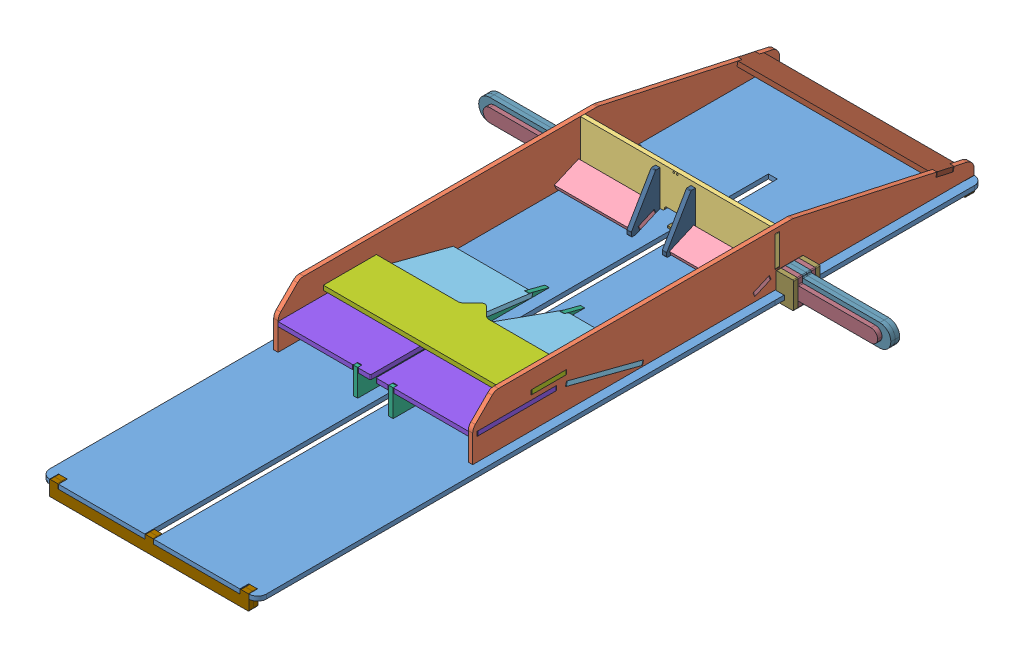
SolidWorks assembly assembly plane folder, configuration Default. Lengths in mm.
Overall size (466 77 820).
30 component instances, 16 part files, 6 mates.
Components (placement in the parent):
- frame-1: frame [Default] at (-2.7129 -3.6474 600) size (245.6 77 820)
  - backplate-1: backplate [Default] at (-118.702 1.298 900) size (245.6 5 820)
  - side-1: side [Default] at (-108.702 86.298 910) x (0 -1 0) z (1 0 0) size (65 566.78 5)
  - side-2: side [Default] at (111.298 86.298 910) x (0 -1 0) z (1 0 0) size (65 566.78 5)
  - frame-folder-1: frame-folder [Default] at (-103.702 21.248 530) size (225 45 5)
  - frame-folder2-1: frame-folder2 [Default] at (111.298 13.9006 564.4496) x (-1 0 0) z (0 -0.916515 -0.4) size (95 30 5)
  - frame-folder2-2: frame-folder2 [Default] at (-18.702 13.8606 564.5413) x (-1 0 0) z (0 -0.916515 -0.4) size (95 30 5)
  - frame-secondfold-1: frame-secondfold [Default] at (-103.702 31.4463 776.7345) x (1 0 0) z (0 0.967829 -0.251609) size (109.34 100 5)
  - frame-secondfold3-1: frame-secondfold3 [Default] at (-18.702 1.298 906.1881) x (0 0 -1) z (1 0 0) size (216.66 35.16 5)
  - frame-secondfold-3: frame-secondfold [Default] at (111.298 36.2855 775.3765) x (-1 0 0) z (0 -0.967829 0.251609) size (109.34 100 5)
  - frame-secondfold3-2: frame-secondfold3 [Default] at (21.298 1.298 906.0881) x (0 0 -1) z (1 0 0) size (216.66 35.16 5)
  - frame-secondfold1-1: frame-secondfold1 [Default] at (-103.702 41.4589 825.6357) x (1 0 0) z (0 1 0) size (225 72.93 5)
  - frame-secondfold4-1: frame-secondfold4 [Default] at (-103.702 31.4589 876.8329) x (1 0 0) z (0 1 0) size (109.5 100.05 5)
  - frame-secondfold4-2: frame-secondfold4 [Default] at (111.298 31.4589 776.6329) x (-1 0 0) z (0 1 0) size (109.5 100.05 5)
  - stopper-1: stopper [Default] at (-109.002 -10.702 1125) size (225.6 17 5)
  - stopper-2: stopper [Default] at (-109.002 -10.702 1120) size (225.6 17 5)
  - stopper-3: stopper [Default] at (-109.002 -10.702 315) size (225.6 17 5)
  - stopper-4: stopper [Default] at (-109.002 -10.702 310) size (225.6 17 5)
  - frame-folder4-1: frame-folder4 [Default] at (-18.702 61.198 535) x (0 -1 0) z (1 0 0) size (52 37.5 5)
  - frame-folder4-2: frame-folder4 [Default] at (21.298 61.198 535) x (0 -1 0) z (1 0 0) size (52 37.5 5)
  - frame-paperholder-1: frame-paperholder [Default] at (-108.702 25.1666 327.6234) x (1 0 0) z (0 -0.976744 0.214407) size (225 30 5)
- A4 paper-1: A4 paper [Default] at (-103.9148 7.9007 1115) x (1 0 0) z (0 1 0) size (210 297 0.1) (hidden)
- slider2-1: slider2 [Default] at (-49.729 -16.7544 842.5) size (466 32.7 30.31)
  - slider2-1-1: slider2-1 [Default] at (-81.7359 9.355 262.5) size (266 30 5)
  - slider2-2-1: slider2-2 [Default] at (-81.7359 9.355 267.5) size (446 30 5)
  - slider2-3-1: slider2-3 [Default] at (-81.7359 9.355 272.5) size (466 30 5)
  - slider2-3-2: slider2-3 [Default] at (-81.7359 9.355 277.5) size (466 30 5)
  - slider2-2-2: slider2-2 [Default] at (-81.7359 9.355 282.5) size (446 30 5)
  - slider2-1-2: slider2-1 [Default] at (-81.7359 9.355 287.5) size (266 30 5)
  - clip2-1: clip2 [Default] at (41.0141 21.655 292.5) x (1 0 0) z (0 1 0) size (20.89 30.31 20.4) (hidden)
Mates (geometry in assembly coordinates):
- Distance3: distance = 2.5 mm anti-aligned: plane of A4 paper-1 through (-103.9148 8.0007 1115) normal (-1 0 0); plane of frame-1/side-1 through (-106.4148 82.6507 1510) normal (1 0 0)
- Distance4: distance = 0.05 mm anti-aligned: plane of slider2-1/slider2-1-2 through (-121.4648 -2.3993 1135) normal (0 1 0); plane of frame-1/backplate-1 through (-121.4148 -2.3493 1500) normal (0 -1 0)
- Distance9: distance = 0.05 mm anti-aligned: plane of frame-1/backplate-1 through (-121.4148 2.6507 1500) normal (-1 0 0); plane of slider2-1/slider2-1-2 through (-121.4648 -2.3993 1135) normal (1 0 0)
- Coincident10: coincident: plane of A4 paper-1 through (-103.9148 8.0007 1115) normal (0 0 1); line of slider2-1/slider2-3-1 through (11.2852 4.9007 1115) axis (-1 0 0)
- LimitDistance2: limit distance = 195 mm aligned: plane of slider2-1/slider2-1-1 through (-131.4648 -7.3993 1105) normal (0 0 -1); plane of frame-1/backplate-1 through (-121.4148 2.6507 910) normal (0 0 -1)
- Distance8: distance = 1 mm anti-aligned: plane of A4 paper-1 through (-103.9148 7.9007 1115) normal (0 -1 0); plane of slider2-1/clip2-1 through (-8.7148 6.9007 1135) normal (0 1 0)
